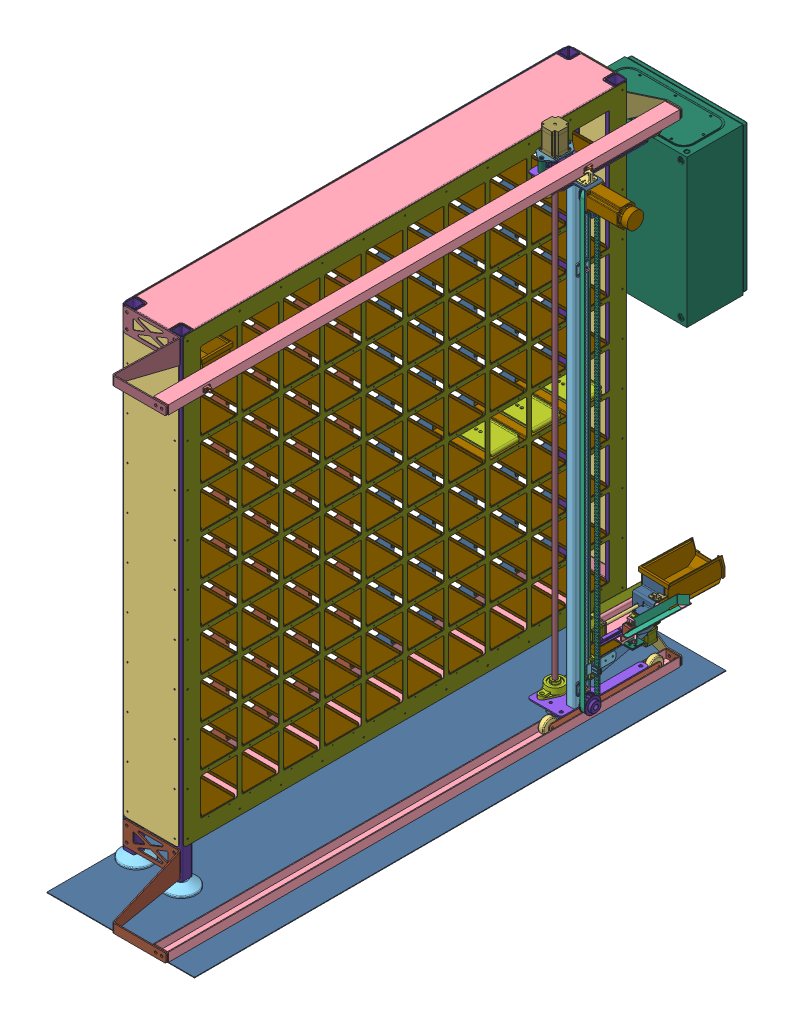
SolidWorks assembly T00000-000-R00, configuration Default. Lengths in mm.
Overall size (585.3 1705.5 1964.8).
258 component instances, 71 part files, 38 mates.
Components (placement in the parent):
- T00001-000-R00-1: T00001-000-R00 [Default] at (541.221 27.0951 939.139) size (309.78 1703.5 1858.33) (flexible)
  - T00118-000-R00-1: T00118-000-R00 [Default] at (157.9488 226.0018 -468.9511) size (25 25 300)
  - T00119-DXF-R00-1: T00119-DXF-R00 [Default] at (145.4488 226.0018 -318.9511) x (0 0 1) z (0 -1 0) size (380 3 25)
  - T00119-DXF-R00-2: T00119-DXF-R00 [Default] at (173.4488 226.0018 -318.9511) x (0 0 -1) z (0 1 0) size (380 3 25)
  - T00103-E00-R00-1: T00103-E00-R00 [Default] at (157.9488 226.0018 -138.9511) x (0 -0.996374 0.085085) z (0 0.085085 0.996374) size (50 22 50)
  - T00103-E00-R00-2: T00103-E00-R00 [Default] at (157.9488 226.0018 -498.9511) x (0 -1 0) z (0 0 1) size (50 22 50)
  - T00117-000-R00-1: T00117-000-R00 [Default] at (157.9488 198.0018 -560.9511) size (50 30 1732)
  - T00112-000-R00-1: T00112-000-R00 [50 x 30 x 2.6x1700] at (142.9488 1012.5018 -263.9511) x (1 0 0) z (0 -1 0) size (30 50 1540)
  - T00109-E00-R00-1: T00109-E00-R00 [HGR15R400CE20] at (157.9488 1772.5018 -263.9511) x (1 0 0) z (0 1 0) size (15 15 1530)
  - T00100-E00-R00-4: T00100-E00-R00 [Default] at (82.9488 242.5018 -238.9511) x (0 1 0) z (0 0 1) size (65.14 65.88 113)
  - T00120-DXF-R00-1: T00120-DXF-R00 [Default] at (100.4488 238.5018 -238.9511) x (0 0 -1) z (-1 0 0) size (300 4 115)
  - T00120-DXF-R00-2: T00120-DXF-R00 [Default] at (100.4488 1782.5018 -238.9511) x (0 0 -1) z (-1 0 0) size (300 4 115)
  - T00100-E00-R00-2: T00100-E00-R00 [Default] at (82.9488 1782.5018 -238.9511) x (0 -1 0) z (0 0 -1) size (65.14 65.88 113)
  - T00160-E00-R00-8: T00160-E00-R00 [Default] at (216.9488 1755.5018 -238.9511) x (0 0 1) z (-1 0 0) size (60 69 159.8)
  - T00121-0A4-R00-1: T00121-0A4-R00 [Default] at (216.9488 1751.5018 -238.9511) x (0 0 -1) z (0 -1 0) size (300 74 94)
  - T00103-E00-R00-3: T00103-E00-R00 [Default] at (157.9488 1803.0018 -138.9511) x (0 -1 0) z (0 0 1) size (50 22 50)
  - T00103-E00-R00-4: T00103-E00-R00 [Default] at (157.9488 1803.0018 -498.9511) x (0 0.952135 0.305677) z (0 0.305677 -0.952135) size (50 22 50)
  - T00119-DXF-R00-3: T00119-DXF-R00 [Default] at (173.4488 1803.0018 -318.9511) x (0 0 1) z (0 -1 0) size (380 3 25)
  - T00119-DXF-R00-4: T00119-DXF-R00 [Default] at (145.4488 1803.0018 -318.9511) x (0 0 -1) z (0 1 0) size (380 3 25)
  - T00118-000-R00-2: T00118-000-R00 [Default] at (157.9488 1803.0018 -168.9511) x (1 0 0) z (0 0 -1) size (25 25 300)
  - T00117-000-R00-2: T00117-000-R00 [Default] at (157.9488 1833.5018 -560.9511) x (-1 0 0) z (0 0 1) size (50 30 1732)
  - T00122-DXF-R00-1: T00122-DXF-R00 [Default] at (157.9488 213.0018 1175.0489) size (50 30 4)
  - T00122-DXF-R00-2: T00122-DXF-R00 [Default] at (157.9488 213.0018 -560.9511) size (50 30 4)
  - T00122-DXF-R00-3: T00122-DXF-R00 [Default] at (157.9488 1818.5018 -564.9511) x (-1 0 0) z (0 0 -1) size (50 30 4)
  - T00122-DXF-R00-4: T00122-DXF-R00 [Default] at (157.9488 1818.5018 1175.0489) size (50 30 4)
  - T00106-E00-R00-6: T00106-E00-R00 [Default] at (82.8989 1862.7018 -130.4663) x (-0.013505 0 0.999909) z (0 -1 0) size (56.4 57 96.6)
  - T00123-000-R00-1: T00123-000-R00 [Default] at (82.341 1823.9018 -238.9552) x (1 0 0) z (0 -1 0) size (15 15 1615)
  - T00124-DXF-R00-1: T00124-DXF-R00 [Default] at (82.341 1825.5018 -238.9552) x (-0.013505 0 0.999909) z (-0.999909 0 -0.013505) size (110 4 65)
  - T00104-E00-R00-1: T00104-E00-R00 [Default] at (82.9488 1786.5018 -193.9511) x (0 1 0) z (0 0 1) size (35 20 20)
  - T00104-E00-R00-2: T00104-E00-R00 [Default] at (82.9488 1786.5018 -283.9511) x (0 1 0) z (0 0 1) size (35 20 20)
  - T00101-E00-R00-1: T00101-E00-R00 [Default] at (112.9488 1791.0018 -193.9511) size (22 7 22)
  - T00101-E00-R00-2: T00101-E00-R00 [Default] at (112.9488 1791.0018 -283.9511) size (22 7 22)
  - T00101-E00-R00-3: T00101-E00-R00 [Default] at (112.9488 1798.0018 -283.9511) x (-0.837169 0 -0.546944) z (-0.546944 0 0.837169) size (22 7 22)
  - T00101-E00-R00-4: T00101-E00-R00 [Default] at (112.9488 1798.0018 -193.9511) x (-0.837169 0 -0.546944) z (-0.546944 0 0.837169) size (22 7 22)
  - T00101-E00-R00-5: T00101-E00-R00 [Default] at (112.9488 234.0018 -283.9511) size (22 7 22)
  - T00101-E00-R00-6: T00101-E00-R00 [Default] at (112.9488 227.0018 -283.9511) size (22 7 22)
  - T00101-E00-R00-7: T00101-E00-R00 [Default] at (112.9488 234.0018 -193.9511) x (-0.837169 0 -0.546944) z (-0.546944 0 0.837169) size (22 7 22)
  - T00101-E00-R00-8: T00101-E00-R00 [Default] at (112.9488 227.0018 -193.9511) x (-0.837169 0 -0.546944) z (-0.546944 0 0.837169) size (22 7 22)
  - T00102-E00-R00-1: T00102-E00-R00 [Default] at (82.341 237.5018 -238.9552) x (0 -1 0) z (-0.546944 0 0.837169) size (31 54 54)
  - T00102-E00-R00-2: T00102-E00-R00 [Default] at (82.341 1787.5018 -238.9552) x (0 1 0) z (0 0 1) size (31 54 54)
  - T00102-E00-R00-3: T00102-E00-R00 [Default] at (210.9488 1755.5018 -238.9511) x (-1 0 0) z (0 0.770219 0.637779) size (31 54 54)
  - T00125-0A4-R00-1: T00125-0A4-R00 [Default] at (137.9488 260.2518 -238.9511) x (0 0.966097 0.25818) z (0 0.25818 -0.966097) size (15 71.4 15)
  - T00102-E00-R00-5: T00102-E00-R00 [Default] at (189.9488 260.2518 -238.9511) x (1 0 0) z (0 0.748566 0.66306) size (31 54 54)
  - T00152-03D-R00-4: T00152-03D-R00 [Default] at (172.9488 297.5018 -239.1511) x (0 -1 0) z (0 0 1) size (40 4 40)
  - T00149-E00-R00-2: T00149-E00-R00 [Default] at (195.8488 1815.5018 -247.7511) x (0 0 1) z (0 1 0) size (22.7 14.9 13.4)
  - T00149-E00-R00-3: T00149-E00-R00 [Default] at (195.8488 1821.5018 1041.6323) x (0 0 -1) z (0 -1 0) size (22.7 14.9 13.4)
  - T00150-03D-R00-3: T00150-03D-R00 [Default] at (191.1488 1790.5018 -238.9511) x (0 0 -1) z (1 0 0) size (45 29.75 32)
  - T00153-E00-R00-1: T00153-E00-R00 [Default] at (180.9488 1523.996 -248.1511) x (0 -1 0) z (1 0 0) size (13 22.4 13.7)
  - T00151-03D-R00-1: T00151-03D-R00 [Default] at (172.9488 1527.496 -238.9511) x (0 -1 0) z (0 0 1) size (40 4 40)
  - T00153-E00-R00-2: T00153-E00-R00 [Default] at (180.9488 294.0018 -247.9534) x (0 -1 0) z (1 0 0) size (13 22.4 13.7)
  - T00166-E00-R00-1: T00166-E00-R00 [Default] at (193.6988 1755.5018 107.1126) x (0 0 -1) z (1 0 0) size (52.05 1547.3 15)
  - T00003-000-R00-2: T00003-000-R00 [Default] at (0 -530.7546 -533.6254) size (146.34 185.95 438.31)
    - T00108-E00-R00-3: T00108-E00-R00 [Default] at (157.9488 862.2474 269.7743) x (1 0 0) z (0 1 0) size (34 23.7 61.49)
    - T00110-E00-R00-1: T00110-E00-R00 [HGR15R400CE20] at (179.5179 918.7474 -31.6814) x (-0.999622 0 -0.027507) z (0.027507 0 -0.999622) size (15 15 270)
    - T00108-E00-R00-4: T00108-E00-R00 [Default] at (176.1354 919.5474 91.2378) x (-0.999622 0 -0.027507) z (0.027507 0 -0.999622) size (34 23.7 61.49)
    - T00148-E00-R00-1: T00148-E00-R00 [Default] at (211.9326 941.2474 40.4812) x (-0.999622 0 -0.027507) z (0.027507 0 -0.999622) size (104.77 76.2 187.32)
    - T00126-000-R00-1: T00126-000-R00 [Default] at (176.1354 950.5474 91.2378) x (-0.999622 0 -0.027507) z (0 1 0) size (75 74 94)
    - T00127-E00-R00-1: T00127-E00-R00 [DIN 625 - 6002 - 12,SI,NC,12_68] at (157.9488 901.2474 97.7743) x (0 1 0) z (0 0 1) size (9 32 32)
    - T00128-0A4-R00-1: T00128-0A4-R00 [Default] at (157.9488 887.7474 97.7743) x (1 0 0) z (0 -1 0) size (25 25 21)
    - T00129-E00-R00-1: T00129-E00-R00 [Circlip DIN 471 - 15 x 1.5] at (157.9488 905.9474 97.7743) x (0.837169 0 0.546944) z (0 -1 0) size (17.74 21.49 1.5)
    - T00130-0A4-R01-1: T00130-0A4-R01 [Default] at (157.9488 895.7474 97.7743) x (0.027507 0 -0.999622) z (0 -1 0) size (90 90 20)
    - T00132-E00-R00-4: T00132-E00-R00 [Metric - Spur gear 1M 60T 20PA 9FW ---S60N75H50L42N] at (157.9488 896.7474 97.7743) x (0 1 0) z (0 0 1) size (9 61.95 61.95)
    - T00107-E00-R00-1: T00107-E00-R00 [Varsayılan] at (157.9488 879.7474 61.7743) x (-1 0 0) z (0 1 0) size (42 58.5 65.65)
    - T00131-E00-R00-2: T00131-E00-R00 [Metric - Spur gear 1M 12T 20PA 8FW ---S12O10H14L5N] at (157.9488 896.7474 61.7743) x (0 1 0) z (0.924225 0 0.381849) size (14 13.61 13.61)
    - T00133-0A4-R00-3: T00133-0A4-R00 [Default] at (157.9488 862.2474 237.7743) x (1 0 0) z (0 1 0) size (49 210 57)
    - T00134-DXF-R00-1: T00134-DXF-R00 [Default] at (130.4488 892.7474 239.7743) x (0 0 -1) z (-1 0 0) size (155 44.25 3)
    - T00134-DXF-R00-2: T00134-DXF-R00 [Default] at (182.4488 892.7474 239.7743) x (0 0 -1) z (-1 0 0) size (155 44.25 3)
    - T00105-E00-R00-1: T00105-E00-R00 [Default] at (142.4488 890.7474 46.2743) x (1 0 0) z (0 -1 0) size (6 6 11)
    - T00105-E00-R00-2: T00105-E00-R00 [Default] at (173.4488 890.7474 46.2743) x (0.974973 0 -0.222324) z (0 -1 0) size (6 6 11)
    - T00105-E00-R00-3: T00105-E00-R00 [Default] at (142.4488 890.7474 77.2743) x (1 0 0) z (0 -1 0) size (6 6 11)
    - T00105-E00-R00-4: T00105-E00-R00 [Default] at (173.4488 890.7474 77.2743) x (1 0 0) z (0 -1 0) size (6 6 11)
    - T00107-E00-R00-2: T00107-E00-R00 [Varsayılan] at (132.7203 933.2474 196.6177) x (0.999622 0 0.027507) z (0.027507 0 -0.999622) size (42 58.5 65.65)
    - T00111-E00-R00-1: T00111-E00-R00 [Default] at (139.377 933.2474 -45.2907) x (0.577812 0.816015 0.0159) z (0.815706 -0.578031 0.022446) size (10 240 10)
    - T00135-DXF-R01-1: T00135-DXF-R01 [Default] at (158.3614 918.7474 82.78) x (-0.027507 0 0.999622) z (-0.999622 0 -0.027507) size (219 39 131)
    - T00136-DXF-R01-1: T00136-DXF-R01 [Default] at (187.4488 877.7474 233.7743) x (0 0 -1) z (1 0 0) size (94.88 30 25)
    - T00137-000-R00-1: T00137-000-R00 [gespiegeld] at (209.9194 941.2474 8.6701) x (0.027507 0 -0.999622) z (0.999622 0 0.027507) size (201.93 32 21.92)
    - T00138-000-R00-1: T00138-000-R00 [gespiegeld] at (111.9565 941.2474 5.9745) x (0.027507 0 -0.999622) z (0.999622 0 0.027507) size (201.93 32 21.92)
    - T00162-03D-R00-1: T00162-03D-R00 [Default] at (157.9488 905.7474 97.7743) x (0.027507 0 -0.999622) z (0 -1 0) size (22 26.53 4.1)
    - T00153-E00-R00-4: T00153-E00-R00 [Default] at (207.435 977.2474 171.6635) x (0.027507 0 -0.999622) z (0 1 0) size (13 22.4 13.7)
    - socket head cap screw_iso-1: socket head cap screw_iso [ISO 4762 M3 x 16 - 16N] at (223.2364 978.7474 179.1009) x (0 -1 0) z (0.997971 0 0.063667) size (19 5.5 5.5)
    - hex nut style 1 gradeab_iso-1: hex nut style 1 gradeab_iso [ISO - 4032 - M3 - W - N] at (223.2364 965.2474 179.1009) x (1 0 0) z (0 1 0) size (5.5 6.35 2.4)
    - socket head cap screw_iso-2: socket head cap screw_iso [ISO 4762 M3 x 16 - 16N] at (216.2391 978.7474 178.9084) x (0 -1 0) z (0 0 1) size (19 5.5 5.5)
    - socket head cap screw_iso-3: socket head cap screw_iso [ISO 4762 M3 x 8 - 8N] at (212.2406 949.2474 178.7984) x (-0.999622 0 -0.027507) z (0.027393 0.090831 -0.995489) size (11 5.5 5.5)
    - socket head cap screw_iso-4: socket head cap screw_iso [ISO 4762 M3 x 8 - 8N] at (212.2406 957.2474 178.7984) x (-0.999622 0 -0.027507) z (0.020371 -0.671964 -0.740304) size (11 5.5 5.5)
    - hex nut style 1 gradeab_iso-3: hex nut style 1 gradeab_iso [ISO - 4032 - M3 - W - N] at (216.2391 965.4397 178.9084) x (0.95019 0 0.311672) z (0 1 0) size (5.5 6.35 2.4)
    - hex nut style 1 gradeab_iso-4: hex nut style 1 gradeab_iso [ISO - 4032 - M3 - W - N] at (204.2436 957.2474 178.5783) x (0.020371 -0.671964 -0.740304) z (0.999622 0 0.027507) size (5.5 6.35 2.4)
    - hex nut style 1 gradeab_iso-5: hex nut style 1 gradeab_iso [ISO - 4032 - M3 - W - N] at (204.2436 949.2474 178.5783) x (0.020371 -0.671964 -0.740304) z (0.999622 0 0.027507) size (5.5 6.35 2.4)
    - socket head cap screw_iso-8: socket head cap screw_iso [ISO 4762 M4 x 10 - 10N] at (158.994 897.7474 59.7887) x (0 1 0) z (0.50631 0 0.862351) size (14 7 7)
    - T00153-E00-R00-7: T00153-E00-R00 [Default] at (120.7549 900.9974 134.9681) x (0.707107 0 0.707107) z (0 1 0) size (13 22.4 13.7)
    - T00153-E00-R00-8: T00153-E00-R00 [Default] at (195.1426 900.9974 134.9681) x (0.707107 0 -0.707107) z (0 1 0) size (13 22.4 13.7)
    - socket head cap screw_iso-11: socket head cap screw_iso [ISO 4762 M3 x 6 - 6N] at (168.9902 898.7474 60.0638) x (0 1 0) z (0 0 1) size (9 5.5 5.5)
    - socket head cap screw_iso-13: socket head cap screw_iso [ISO 4762 M3 x 6 - 6N] at (148.9978 898.7474 59.5136) x (0 1 0) z (-0.359477 0 -0.933154) size (9 5.5 5.5)
    - T00168-03D-R00-2: T00168-03D-R00 [Default] at (205.2432 959.2474 178.6058) x (0.027507 0 -0.999622) z (0.999622 0 0.027507) size (20 28 25.65)
    - T00163-03D-R00-1: T00163-03D-R00 [Default] at (179.6935 970.5474 52.8211) x (0.999622 0 0.027507) z (0 1 0) size (49 20 18.45)
    - T00161-0A4-R00-2: T00161-0A4-R00 [Default] at (157.9488 894.7474 147.7835) size (125 2 45)
    - T00164-03D-R00-1: T00164-03D-R00 [Default] at (157.9488 896.7474 147.7835) x (1 0 0) z (0 1 0) size (32 42.2 3)
    - T00165-03D-R00-1: T00165-03D-R00 [Default] at (250.9488 896.7474 147.7835) x (1 0 0) z (0 1 0) size (32 42.2 3)
- T00002-000-R00-1: T00002-000-R00 [Default] at (-702.7967 301.9782 1483.2641) x (0 0 -1) z (1 0 0) size (1575.8 1630 263)
  - T00114-DXF-R00-1: T00114-DXF-R00 [Default] at (354.4761 803.1187 1246.9664) size (1500 1500 2)
  - T00113-000-R00-9: T00113-000-R00 [40 x 40 x 3.2x1600] at (1070.8761 753.1187 1084.9664) x (0 0 -1) z (0 -1 0) size (40 40 1600)
  - T00113-000-R00-6: T00113-000-R00 [40 x 40 x 3.2x1600] at (-401.9239 753.1187 1204.9664) x (1 0 0) z (0 -1 0) size (40 40 1600)
  - T00113-000-R00-10: T00113-000-R00 [40 x 40 x 3.2x1600] at (-401.9239 753.1187 1084.9664) x (1 0 0) z (0 1 0) size (40 40 1600)
  - T00113-000-R00-8: T00113-000-R00 [40 x 40 x 3.2x1600] at (1070.8761 753.1187 1244.9664) x (1 0 0) z (0 1 0) size (40 40 1600)
  - T00116-0A4-R00-1: T00116-0A4-R00 [Default] at (-275.5239 1370.6187 1144.9664) x (0 0 -1) z (0 -1 0) size (200 114 23)
  - T00116-0A4-R00-2: T00116-0A4-R00 [Default] at (-275.5239 1230.6187 1144.9664) x (0 0 -1) z (0 -1 0) size (200 114 23)
  - T00116-0A4-R00-3: T00116-0A4-R00 [Default] at (-275.5239 1090.6187 1144.9664) x (0 0 -1) z (0 -1 0) size (200 114 23)
  - T00116-0A4-R00-4: T00116-0A4-R00 [Default] at (-275.5239 950.6187 1144.9664) x (0 0 -1) z (0 -1 0) size (200 114 23)
  - T00116-0A4-R00-5: T00116-0A4-R00 [Default] at (-275.5239 810.6187 1144.9664) x (0 0 -1) z (0 -1 0) size (200 114 23)
  - T00116-0A4-R00-6: T00116-0A4-R00 [Default] at (-275.5239 670.6187 1144.9664) x (0 0 -1) z (0 -1 0) size (200 114 23)
  - T00116-0A4-R00-7: T00116-0A4-R00 [Default] at (-275.5239 530.6187 1144.9664) x (0 0 -1) z (0 -1 0) size (200 114 23)
  - T00116-0A4-R00-8: T00116-0A4-R00 [Default] at (-275.5239 390.6187 1144.9664) x (0 0 -1) z (0 -1 0) size (200 114 23)
  - T00116-0A4-R00-9: T00116-0A4-R00 [Default] at (-275.5239 250.6187 1144.9664) x (0 0 -1) z (0 -1 0) size (200 114 23)
  - T00116-0A4-R00-10: T00116-0A4-R00 [Default] at (-275.5239 110.6187 1144.9664) x (0 0 -1) z (0 -1 0) size (200 114 23)
  - T00116-0A4-R00-11: T00116-0A4-R00 [Default] at (-135.5239 1370.6187 1144.9664) x (0 0 -1) z (0 -1 0) size (200 114 23)
  - T00116-0A4-R00-12: T00116-0A4-R00 [Default] at (-135.5239 1230.6187 1144.9664) x (0 0 -1) z (0 -1 0) size (200 114 23)
  - T00116-0A4-R00-13: T00116-0A4-R00 [Default] at (-135.5239 1090.6187 1144.9664) x (0 0 -1) z (0 -1 0) size (200 114 23)
  - T00116-0A4-R00-14: T00116-0A4-R00 [Default] at (-135.5239 950.6187 1144.9664) x (0 0 -1) z (0 -1 0) size (200 114 23)
  - T00116-0A4-R00-15: T00116-0A4-R00 [Default] at (-135.5239 810.6187 1144.9664) x (0 0 -1) z (0 -1 0) size (200 114 23)
  - T00116-0A4-R00-16: T00116-0A4-R00 [Default] at (-135.5239 670.6187 1144.9664) x (0 0 -1) z (0 -1 0) size (200 114 23)
  - T00116-0A4-R00-17: T00116-0A4-R00 [Default] at (-135.5239 530.6187 1144.9664) x (0 0 -1) z (0 -1 0) size (200 114 23)
  - T00116-0A4-R00-18: T00116-0A4-R00 [Default] at (-135.5239 390.6187 1144.9664) x (0 0 -1) z (0 -1 0) size (200 114 23)
  - T00116-0A4-R00-19: T00116-0A4-R00 [Default] at (-135.5239 250.6187 1144.9664) x (0 0 -1) z (0 -1 0) size (200 114 23)
  - T00116-0A4-R00-20: T00116-0A4-R00 [Default] at (-135.5239 110.6187 1144.9664) x (0 0 -1) z (0 -1 0) size (200 114 23)
  - T00116-0A4-R00-21: T00116-0A4-R00 [Default] at (4.4761 1370.6187 1144.9664) x (0 0 -1) z (0 -1 0) size (200 114 23)
  - T00116-0A4-R00-22: T00116-0A4-R00 [Default] at (4.4761 1230.6187 1144.9664) x (0 0 -1) z (0 -1 0) size (200 114 23)
  - T00116-0A4-R00-23: T00116-0A4-R00 [Default] at (4.4761 1090.6187 1144.9664) x (0 0 -1) z (0 -1 0) size (200 114 23)
  - T00116-0A4-R00-24: T00116-0A4-R00 [Default] at (4.4761 950.6187 1144.9664) x (0 0 -1) z (0 -1 0) size (200 114 23)
  - T00116-0A4-R00-25: T00116-0A4-R00 [Default] at (4.4761 810.6187 1144.9664) x (0 0 -1) z (0 -1 0) size (200 114 23)
  - T00116-0A4-R00-26: T00116-0A4-R00 [Default] at (4.4761 670.6187 1144.9664) x (0 0 -1) z (0 -1 0) size (200 114 23)
  - T00116-0A4-R00-27: T00116-0A4-R00 [Default] at (4.4761 530.6187 1144.9664) x (0 0 -1) z (0 -1 0) size (200 114 23)
  - T00116-0A4-R00-28: T00116-0A4-R00 [Default] at (4.4761 390.6187 1144.9664) x (0 0 -1) z (0 -1 0) size (200 114 23)
  - T00116-0A4-R00-29: T00116-0A4-R00 [Default] at (4.4761 250.6187 1144.9664) x (0 0 -1) z (0 -1 0) size (200 114 23)
  - T00116-0A4-R00-30: T00116-0A4-R00 [Default] at (4.4761 110.6187 1144.9664) x (0 0 -1) z (0 -1 0) size (200 114 23)
  - T00116-0A4-R00-31: T00116-0A4-R00 [Default] at (144.4761 1370.6187 1144.9664) x (0 0 -1) z (0 -1 0) size (200 114 23)
  - T00116-0A4-R00-32: T00116-0A4-R00 [Default] at (144.4761 1230.6187 1144.9664) x (0 0 -1) z (0 -1 0) size (200 114 23)
  - T00116-0A4-R00-33: T00116-0A4-R00 [Default] at (144.4761 1090.6187 1144.9664) x (0 0 -1) z (0 -1 0) size (200 114 23)
  - T00116-0A4-R00-34: T00116-0A4-R00 [Default] at (144.4761 950.6187 1144.9664) x (0 0 -1) z (0 -1 0) size (200 114 23)
  - T00116-0A4-R00-35: T00116-0A4-R00 [Default] at (144.4761 810.6187 1144.9664) x (0 0 -1) z (0 -1 0) size (200 114 23)
  - T00116-0A4-R00-36: T00116-0A4-R00 [Default] at (144.4761 670.6187 1144.9664) x (0 0 -1) z (0 -1 0) size (200 114 23)
  - T00116-0A4-R00-37: T00116-0A4-R00 [Default] at (144.4761 530.6187 1144.9664) x (0 0 -1) z (0 -1 0) size (200 114 23)
  - T00116-0A4-R00-38: T00116-0A4-R00 [Default] at (144.4761 390.6187 1144.9664) x (0 0 -1) z (0 -1 0) size (200 114 23)
  - T00116-0A4-R00-39: T00116-0A4-R00 [Default] at (144.4761 250.6187 1144.9664) x (0 0 -1) z (0 -1 0) size (200 114 23)
  - T00116-0A4-R00-40: T00116-0A4-R00 [Default] at (144.4761 110.6187 1144.9664) x (0 0 -1) z (0 -1 0) size (200 114 23)
  - T00116-0A4-R00-41: T00116-0A4-R00 [Default] at (284.4761 1370.6187 1144.9664) x (0 0 -1) z (0 -1 0) size (200 114 23)
  - T00116-0A4-R00-42: T00116-0A4-R00 [Default] at (284.4761 1230.6187 1144.9664) x (0 0 -1) z (0 -1 0) size (200 114 23)
  - T00116-0A4-R00-43: T00116-0A4-R00 [Default] at (284.4761 1090.6187 1144.9664) x (0 0 -1) z (0 -1 0) size (200 114 23)
  - T00116-0A4-R00-44: T00116-0A4-R00 [Default] at (284.4761 950.6187 1144.9664) x (0 0 -1) z (0 -1 0) size (200 114 23)
  - T00116-0A4-R00-45: T00116-0A4-R00 [Default] at (284.4761 810.6187 1144.9664) x (0 0 -1) z (0 -1 0) size (200 114 23)
  - T00116-0A4-R00-46: T00116-0A4-R00 [Default] at (284.4761 670.6187 1144.9664) x (0 0 -1) z (0 -1 0) size (200 114 23)
  - T00116-0A4-R00-47: T00116-0A4-R00 [Default] at (284.4761 530.6187 1144.9664) x (0 0 -1) z (0 -1 0) size (200 114 23)
  - T00116-0A4-R00-48: T00116-0A4-R00 [Default] at (284.4761 390.6187 1144.9664) x (0 0 -1) z (0 -1 0) size (200 114 23)
  - T00116-0A4-R00-49: T00116-0A4-R00 [Default] at (284.4761 250.6187 1144.9664) x (0 0 -1) z (0 -1 0) size (200 114 23)
  - T00116-0A4-R00-50: T00116-0A4-R00 [Default] at (284.4761 110.6187 1144.9664) x (0 0 -1) z (0 -1 0) size (200 114 23)
  - T00116-0A4-R00-51: T00116-0A4-R00 [Default] at (424.4761 1370.6187 1144.9664) x (0 0 -1) z (0 -1 0) size (200 114 23)
  - T00116-0A4-R00-52: T00116-0A4-R00 [Default] at (424.4761 1230.6187 1144.9664) x (0 0 -1) z (0 -1 0) size (200 114 23)
  - T00116-0A4-R00-53: T00116-0A4-R00 [Default] at (424.4761 1090.6187 1144.9664) x (0 0 -1) z (0 -1 0) size (200 114 23)
  - T00116-0A4-R00-54: T00116-0A4-R00 [Default] at (424.4761 950.6187 1144.9664) x (0 0 -1) z (0 -1 0) size (200 114 23)
  - T00116-0A4-R00-55: T00116-0A4-R00 [Default] at (424.4761 810.6187 1144.9664) x (0 0 -1) z (0 -1 0) size (200 114 23)
  - T00116-0A4-R00-56: T00116-0A4-R00 [Default] at (424.4761 670.6187 1144.9664) x (0 0 -1) z (0 -1 0) size (200 114 23)
  - T00116-0A4-R00-57: T00116-0A4-R00 [Default] at (424.4761 530.6187 1144.9664) x (0 0 -1) z (0 -1 0) size (200 114 23)
  - T00116-0A4-R00-58: T00116-0A4-R00 [Default] at (424.4761 390.6187 1144.9664) x (0 0 -1) z (0 -1 0) size (200 114 23)
  - T00116-0A4-R00-59: T00116-0A4-R00 [Default] at (424.4761 250.6187 1144.9664) x (0 0 -1) z (0 -1 0) size (200 114 23)
  - T00116-0A4-R00-60: T00116-0A4-R00 [Default] at (424.4761 110.6187 1144.9664) x (0 0 -1) z (0 -1 0) size (200 114 23)
  - T00116-0A4-R00-61: T00116-0A4-R00 [Default] at (564.4761 1370.6187 1144.9664) x (0 0 -1) z (0 -1 0) size (200 114 23)
  - T00116-0A4-R00-62: T00116-0A4-R00 [Default] at (564.4761 1230.6187 1144.9664) x (0 0 -1) z (0 -1 0) size (200 114 23)
  - T00116-0A4-R00-63: T00116-0A4-R00 [Default] at (564.4761 1090.6187 1144.9664) x (0 0 -1) z (0 -1 0) size (200 114 23)
  - T00116-0A4-R00-64: T00116-0A4-R00 [Default] at (564.4761 950.6187 1144.9664) x (0 0 -1) z (0 -1 0) size (200 114 23)
  - T00116-0A4-R00-65: T00116-0A4-R00 [Default] at (564.4761 810.6187 1144.9664) x (0 0 -1) z (0 -1 0) size (200 114 23)
  - T00116-0A4-R00-66: T00116-0A4-R00 [Default] at (564.4761 670.6187 1144.9664) x (0 0 -1) z (0 -1 0) size (200 114 23)
  - T00116-0A4-R00-67: T00116-0A4-R00 [Default] at (564.4761 530.6187 1144.9664) x (0 0 -1) z (0 -1 0) size (200 114 23)
  - T00116-0A4-R00-68: T00116-0A4-R00 [Default] at (564.4761 390.6187 1144.9664) x (0 0 -1) z (0 -1 0) size (200 114 23)
  - T00116-0A4-R00-69: T00116-0A4-R00 [Default] at (564.4761 250.6187 1144.9664) x (0 0 -1) z (0 -1 0) size (200 114 23)
  - T00116-0A4-R00-70: T00116-0A4-R00 [Default] at (564.4761 110.6187 1144.9664) x (0 0 -1) z (0 -1 0) size (200 114 23)
  - T00116-0A4-R00-71: T00116-0A4-R00 [Default] at (704.4761 1370.6187 1144.9664) x (0 0 -1) z (0 -1 0) size (200 114 23)
  - T00116-0A4-R00-72: T00116-0A4-R00 [Default] at (704.4761 1230.6187 1144.9664) x (0 0 -1) z (0 -1 0) size (200 114 23)
  - T00116-0A4-R00-73: T00116-0A4-R00 [Default] at (704.4761 1090.6187 1144.9664) x (0 0 -1) z (0 -1 0) size (200 114 23)
  - T00116-0A4-R00-74: T00116-0A4-R00 [Default] at (704.4761 950.6187 1144.9664) x (0 0 -1) z (0 -1 0) size (200 114 23)
  - T00116-0A4-R00-75: T00116-0A4-R00 [Default] at (704.4761 810.6187 1144.9664) x (0 0 -1) z (0 -1 0) size (200 114 23)
  - T00116-0A4-R00-77: T00116-0A4-R00 [Default] at (704.4761 530.6187 1144.9664) x (0 0 -1) z (0 -1 0) size (200 114 23)
  - T00116-0A4-R00-78: T00116-0A4-R00 [Default] at (704.4761 390.6187 1144.9664) x (0 0 -1) z (0 -1 0) size (200 114 23)
  - T00116-0A4-R00-79: T00116-0A4-R00 [Default] at (704.4761 250.6187 1144.9664) x (0 0 -1) z (0 -1 0) size (200 114 23)
  - T00116-0A4-R00-80: T00116-0A4-R00 [Default] at (704.4761 110.6187 1144.9664) x (0 0 -1) z (0 -1 0) size (200 114 23)
  - T00116-0A4-R00-81: T00116-0A4-R00 [Default] at (844.4761 1370.6187 1144.9664) x (0 0 -1) z (0 -1 0) size (200 114 23)
  - T00116-0A4-R00-82: T00116-0A4-R00 [Default] at (844.4761 1230.6187 1144.9664) x (0 0 -1) z (0 -1 0) size (200 114 23)
  - T00116-0A4-R00-83: T00116-0A4-R00 [Default] at (844.4761 1090.6187 1144.9664) x (0 0 -1) z (0 -1 0) size (200 114 23)
  - T00116-0A4-R00-84: T00116-0A4-R00 [Default] at (844.4761 950.6187 1144.9664) x (0 0 -1) z (0 -1 0) size (200 114 23)
  - T00116-0A4-R00-85: T00116-0A4-R00 [Default] at (844.4761 810.6187 1144.9664) x (0 0 -1) z (0 -1 0) size (200 114 23)
  - T00116-0A4-R00-87: T00116-0A4-R00 [Default] at (844.4761 530.6187 1144.9664) x (0 0 -1) z (0 -1 0) size (200 114 23)
  - T00116-0A4-R00-88: T00116-0A4-R00 [Default] at (844.4761 390.6187 1144.9664) x (0 0 -1) z (0 -1 0) size (200 114 23)
  - T00116-0A4-R00-89: T00116-0A4-R00 [Default] at (844.4761 250.6187 1144.9664) x (0 0 -1) z (0 -1 0) size (200 114 23)
  - T00116-0A4-R00-90: T00116-0A4-R00 [Default] at (844.4761 110.6187 1144.9664) x (0 0 -1) z (0 -1 0) size (200 114 23)
  - T00116-0A4-R00-91: T00116-0A4-R00 [Default] at (984.4761 1370.6187 1144.9664) x (0 0 -1) z (0 -1 0) size (200 114 23)
  - T00116-0A4-R00-92: T00116-0A4-R00 [Default] at (984.4761 1230.6187 1144.9664) x (0 0 -1) z (0 -1 0) size (200 114 23)
  - T00116-0A4-R00-93: T00116-0A4-R00 [Default] at (984.4761 1090.6187 1144.9664) x (0 0 -1) z (0 -1 0) size (200 114 23)
  - T00116-0A4-R00-94: T00116-0A4-R00 [Default] at (984.4761 950.6187 1144.9664) x (0 0 -1) z (0 -1 0) size (200 114 23)
  - T00116-0A4-R00-95: T00116-0A4-R00 [Default] at (984.4761 810.6187 1144.9664) x (0 0 -1) z (0 -1 0) size (200 114 23)
  - T00116-0A4-R00-97: T00116-0A4-R00 [Default] at (984.4761 530.6187 1144.9664) x (0 0 -1) z (0 -1 0) size (200 114 23)
  - T00116-0A4-R00-98: T00116-0A4-R00 [Default] at (984.4761 390.6187 1144.9664) x (0 0 -1) z (0 -1 0) size (200 114 23)
  - T00116-0A4-R00-99: T00116-0A4-R00 [Default] at (984.4761 250.6187 1144.9664) x (0 0 -1) z (0 -1 0) size (200 114 23)
  - T00116-0A4-R00-100: T00116-0A4-R00 [Default] at (984.4761 110.6187 1144.9664) x (0 0 -1) z (0 -1 0) size (200 114 23)
  - T00115-DXF-R01-1: T00115-DXF-R01 [Default] at (870.8674 -111.1162 2345.3532) x (-1 0 0) z (0 0 -1) size (1500 1500 2)
    - T00158-DXF-R00-1: T00158-DXF-R00 [Default] at (516.3913 914.2349 1302.3867) size (680 1500 2)
    - T00159-DXF-R00-1: T00159-DXF-R00 [Default] at (516.3913 914.2349 1302.3867) size (820 1500 2)
  - T00139-DXF-R00-1: T00139-DXF-R00 [Default] at (1112.8761 53.1187 1238.5664) x (0 0 -1) z (1 0 0) size (187.2 1500 2)
  - T00139-DXF-R00-2: T00139-DXF-R00 [Default] at (-403.9239 53.1187 1051.3664) x (0 0 1) z (-1 0 0) size (187.2 1500 2)
  - T00140-0A4-R00-1: T00140-0A4-R00 [Default] at (354.4761 1551.1187 1144.9664) x (1 0 0) z (0 -1 0) size (1512.8 200 40)
  - T00140-0A4-R00-2: T00140-0A4-R00 [Default] at (354.4761 55.1187 1144.9664) x (1 0 0) z (0 1 0) size (1512.8 200 40)
  - T00141-E00-R00-1: T00141-E00-R00 [SINGLE NUT] at (-374.1239 -76.8813 1065.1664) size (103 100 103)
  - T00141-E00-R00-2: T00141-E00-R00 [SINGLE NUT] at (-381.9239 -76.8813 1224.9664) size (103 100 103)
  - T00141-E00-R00-3: T00141-E00-R00 [SINGLE NUT] at (1090.8761 -76.8813 1064.9664) size (103 100 103)
  - T00141-E00-R00-4: T00141-E00-R00 [SINGLE NUT] at (1090.8761 -76.8813 1224.9664) size (103 100 103)
  - T00004-000-R00-1: T00004-000-R00 [Default] at (704.4761 655.6187 1144.9664) size (114 38.3 200)
    - T00157-E00-R00-1: T00157-E00-R00 [Default] at (0 9.15 27.5) x (0 0 -1) z (-1 0 0) size (80 12.7 12.7)
    - T00156-000-R00-1: T00156-000-R00 [Default] at (0 20.3 0) x (-1 0 0) z (0 1 0) size (106 182 17)
    - flat washer narrow_am-1: flat washer narrow_am [B18.22M - Plain washer, 5 mm, narrow] at (0 2.8 62.5) x (0 1 0) z (0 0 1) size (1.4 11 11)
    - flat washer narrow_am-2: flat washer narrow_am [B18.22M - Plain washer, 5 mm, narrow] at (0 2.8 47.5) x (0 1 0) z (0 0 1) size (1.4 11 11)
    - flat washer narrow_am-3: flat washer narrow_am [B18.22M - Plain washer, 5 mm, narrow] at (0 1.4 62.5) x (0 1 0) z (0 0 1) size (1.4 11 11)
    - flat washer narrow_am-4: flat washer narrow_am [B18.22M - Plain washer, 5 mm, narrow] at (0 1.4 47.5) x (0 1 0) z (-0.546944 0 0.837169) size (1.4 11 11)
    - flat washer narrow_am-7: flat washer narrow_am [B18.22M - Plain washer, 5 mm, narrow] at (0 15.5 -7.5) x (0 -1 0) z (-0.546944 0 0.837169) size (1.4 11 11)
    - flat washer narrow_am-8: flat washer narrow_am [B18.22M - Plain washer, 5 mm, narrow] at (0 16.9 -7.5) x (0 -1 0) z (0 0 1) size (1.4 11 11)
    - flat washer narrow_am-11: flat washer narrow_am [B18.22M - Plain washer, 5 mm, narrow] at (0 15.5 7.5) x (0 -1 0) z (-0.535309 0 -0.844656) size (1.4 11 11)
    - flat washer narrow_am-12: flat washer narrow_am [B18.22M - Plain washer, 5 mm, narrow] at (0 16.9 7.5) x (0 -1 0) z (0 0 1) size (1.4 11 11)
    - T00155-0A3-R00-3: T00155-0A3-R00 [Default] x (0 0 -1) z (0 1 0) size (200 114 23)
  - T00004-000-R00-2: T00004-000-R00 [Default] at (844.4761 655.6187 1144.9664) size (114 38.3 200)
    - T00157-E00-R00-1: T00157-E00-R00 [Default] at (0 9.15 27.5) x (0 0 -1) z (-1 0 0) size (80 12.7 12.7)
    - T00156-000-R00-1: T00156-000-R00 [Default] at (0 20.3 0) x (-1 0 0) z (0 1 0) size (106 182 17)
    - flat washer narrow_am-1: flat washer narrow_am [B18.22M - Plain washer, 5 mm, narrow] at (0 2.8 62.5) x (0 1 0) z (0 0 1) size (1.4 11 11)
    - flat washer narrow_am-2: flat washer narrow_am [B18.22M - Plain washer, 5 mm, narrow] at (0 2.8 47.5) x (0 1 0) z (0 0 1) size (1.4 11 11)
    - flat washer narrow_am-3: flat washer narrow_am [B18.22M - Plain washer, 5 mm, narrow] at (0 1.4 62.5) x (0 1 0) z (0 0 1) size (1.4 11 11)
    - flat washer narrow_am-4: flat washer narrow_am [B18.22M - Plain washer, 5 mm, narrow] at (0 1.4 47.5) x (0 1 0) z (-0.546944 0 0.837169) size (1.4 11 11)
    - flat washer narrow_am-7: flat washer narrow_am [B18.22M - Plain washer, 5 mm, narrow] at (0 15.5 -7.5) x (0 -1 0) z (-0.546944 0 0.837169) size (1.4 11 11)
    - flat washer narrow_am-8: flat washer narrow_am [B18.22M - Plain washer, 5 mm, narrow] at (0 16.9 -7.5) x (0 -1 0) z (0 0 1) size (1.4 11 11)
    - flat washer narrow_am-11: flat washer narrow_am [B18.22M - Plain washer, 5 mm, narrow] at (0 15.5 7.5) x (0 -1 0) z (-0.535309 0 -0.844656) size (1.4 11 11)
    - flat washer narrow_am-12: flat washer narrow_am [B18.22M - Plain washer, 5 mm, narrow] at (0 16.9 7.5) x (0 -1 0) z (0 0 1) size (1.4 11 11)
    - T00155-0A3-R00-3: T00155-0A3-R00 [Default] x (0 0 -1) z (0 1 0) size (200 114 23)
  - T00004-000-R00-3: T00004-000-R00 [Default] at (984.4761 655.6187 1144.9664) size (114 38.3 200)
    - T00157-E00-R00-1: T00157-E00-R00 [Default] at (0 9.15 27.5) x (0 0 -1) z (-1 0 0) size (80 12.7 12.7)
    - T00156-000-R00-1: T00156-000-R00 [Default] at (0 20.3 0) x (-1 0 0) z (0 1 0) size (106 182 17)
    - flat washer narrow_am-1: flat washer narrow_am [B18.22M - Plain washer, 5 mm, narrow] at (0 2.8 62.5) x (0 1 0) z (0 0 1) size (1.4 11 11)
    - flat washer narrow_am-2: flat washer narrow_am [B18.22M - Plain washer, 5 mm, narrow] at (0 2.8 47.5) x (0 1 0) z (0 0 1) size (1.4 11 11)
    - flat washer narrow_am-3: flat washer narrow_am [B18.22M - Plain washer, 5 mm, narrow] at (0 1.4 62.5) x (0 1 0) z (0 0 1) size (1.4 11 11)
    - flat washer narrow_am-4: flat washer narrow_am [B18.22M - Plain washer, 5 mm, narrow] at (0 1.4 47.5) x (0 1 0) z (-0.546944 0 0.837169) size (1.4 11 11)
    - flat washer narrow_am-7: flat washer narrow_am [B18.22M - Plain washer, 5 mm, narrow] at (0 15.5 -7.5) x (0 -1 0) z (-0.546944 0 0.837169) size (1.4 11 11)
    - flat washer narrow_am-8: flat washer narrow_am [B18.22M - Plain washer, 5 mm, narrow] at (0 16.9 -7.5) x (0 -1 0) z (0 0 1) size (1.4 11 11)
    - flat washer narrow_am-11: flat washer narrow_am [B18.22M - Plain washer, 5 mm, narrow] at (0 15.5 7.5) x (0 -1 0) z (-0.535309 0 -0.844656) size (1.4 11 11)
    - flat washer narrow_am-12: flat washer narrow_am [B18.22M - Plain washer, 5 mm, narrow] at (0 16.9 7.5) x (0 -1 0) z (0 0 1) size (1.4 11 11)
    - T00155-0A3-R00-3: T00155-0A3-R00 [Default] x (0 0 -1) z (0 1 0) size (200 114 23)
- T00147-E00-R00-1: T00147-E00-R00 [Default] at (562.1697 225.0969 1210.1879) x (0 0 1) z (0 1 0) size (1800 500 2)
- T00142-0A4-R00-2: T00142-0A4-R00 [Default] at (442.1697 310.0969 1885.1879) x (-1 0 0) z (0 0 -1) size (375.6 125.46 233)
- T00143-DXF-R00-1: T00143-DXF-R00 [Default] at (442.1697 310.0969 370.1879) x (-1 0 0) z (0 0 -1) size (375.6 125 4)
- T00143-DXF-R00-2: T00143-DXF-R00 [Default] at (442.1697 1775.5969 374.1879) x (-1 0 0) z (0 0 1) size (375.6 125 4)
- T00144-0A4-R00-1: T00144-0A4-R00 [Default] at (442.1697 1815.5969 1885.1879) x (-1 0 0) z (0 0 -1) size (375.6 85.45 233)
- T00145-E00-R00-1: T00145-E00-R00 [Default] at (654.1697 247.0969 745.1879) x (-0.837169 0 -0.546944) z (-0.546944 0 0.837169) size (22 7 22)
- T00145-E00-R00-2: T00145-E00-R00 [Default] at (654.1697 247.0969 655.1879) x (-0.837169 0 -0.546944) z (-0.546944 0 0.837169) size (22 7 22)
- T00146-E00-R00-1: T00146-E00-R00 [Default] at (540.1697 1725.0969 265.3879) x (1 0 0) z (0 0 -1) size (400 500 217)
- T00148-E00-R00-1: T00148-E00-R00 [Default] at (539.4947 1673.5969 1706.4004) x (0 0 1) z (-1 0 0) size (104.77 76.2 187.32)
- T00169-E00-R00-1: T00169-E00-R00 [Default] at (540.1697 1635.4469 163.7879) x (1 0 0) z (0 -1 0) size (166 14.1 124.15)
- T00170-03D-R00-1: T00170-03D-R00 [Default] at (540.1697 1635.4469 161.8879) x (-1 0 0) z (0 0 -1) size (184 131.9 18.8)
Mates (geometry in assembly coordinates):
- Distance1: distance = 130 mm: plane of T00002-000-R00-1/T00114-DXF-R00-1 through (544.1697 1105.0969 1128.7879) normal (1 0 0); plane of T00001-000-R00-1/T00117-000-R00-1 through (674.1697 225.0969 2110.1879) normal (-1 0 0)
- Distance2: distance = 225 mm: plane of T00002-000-R00-1/T00113-000-R00-6 through (508.5697 255.0969 1885.1879) normal (0 0 1); plane of T00001-000-R00-1/T00117-000-R00-1 through (699.1697 225.0969 2110.1879) normal (0 0 1)
- Distance3: distance = 30 mm: plane of T00001-000-R00-1/T00117-000-R00-1 through (674.1697 225.0969 2110.1879) normal (0 -1 0); plane of T00002-000-R00-1/T00113-000-R00-8 through (508.5697 255.0969 378.7879) normal (0 -1 0)
- Coincident4: coincident: plane of T00001-000-R00-1/T00117-000-R00-1 through (674.1697 225.0969 2110.1879) normal (0 -1 0); plane of T00147-E00-R00-1 through (562.1697 225.0969 1210.1879) normal (0 1 0)
- Distance4: distance = 30 mm: plane of T00147-E00-R00-1 through (312.1697 223.0969 310.1879) normal (-1 0 0); plane of T00002-000-R00-1/T00113-000-R00-10 through (342.1697 1855.0969 1851.5879) normal (-1 0 0)
- Coincident6: coincident: plane of T00001-000-R00-1/T00117-000-R00-1 through (699.1697 225.0969 2110.1879) normal (0 0 1); plane of T00147-E00-R00-1 through (312.1697 223.0969 2110.1879) normal (0 0 1)
- Coincident8: coincident: plane of T00002-000-R00-1/T00113-000-R00-10 through (375.7697 1855.0969 1885.1879) normal (0 0 1); plane of T00142-0A4-R00-2 through (442.1697 310.0969 1885.1879) normal (0 0 -1)
- Distance5: distance = 6.4 mm: plane of T00002-000-R00-1/T00113-000-R00-10 through (342.1697 1855.0969 1851.5879) normal (-1 0 0); plane of T00142-0A4-R00-2 through (348.5697 270.0969 1889.1879) normal (-1 0 0)
- Distance6: distance = 5 mm: plane of T00142-0A4-R00-2 through (535.7697 350.0969 1889.1879) normal (0 1 0); plane of T00002-000-R00-1/T00139-DXF-R00-2 through (358.5697 355.0969 1885.1879) normal (0 -1 0)
- Coincident9: coincident: plane of T00001-000-R00-1/T00122-DXF-R00-2 through (679.1697 230.0969 374.1879) normal (0 0 -1); plane of T00143-DXF-R00-1 through (442.1697 310.0969 374.1879) normal (0 0 1)
- Concentric1: concentric: cylinder of T00001-000-R00-1/T00122-DXF-R00-2 through (689.1697 240.0969 374.1879) axis (0 0 1) radius 4.25; cylinder of T00143-DXF-R00-1 through (689.1697 240.0969 374.1879) axis (0 0 -1) radius 4.25
- Concentric2: concentric: cylinder of T00001-000-R00-1/T00122-DXF-R00-2 through (709.1697 240.0969 374.1879) axis (0 0 1) radius 4.25; cylinder of T00143-DXF-R00-1 through (709.1697 240.0969 374.1879) axis (0 0 -1) radius 4.25
- Coincident10: coincident: plane of T00001-000-R00-1/T00122-DXF-R00-3 through (719.1697 1835.5969 374.1879) normal (0 0 -1); plane of T00143-DXF-R00-2 through (442.1697 1775.5969 374.1879) normal (0 0 1)
- Concentric3: concentric: cylinder of T00001-000-R00-1/T00122-DXF-R00-3 through (709.1697 1845.5969 378.1879) axis (0 0 -1) radius 4.25; cylinder of T00143-DXF-R00-2 through (709.1697 1845.5969 370.1879) axis (0 0 1) radius 4.25
- Concentric4: concentric: cylinder of T00001-000-R00-1/T00122-DXF-R00-3 through (689.1697 1845.5969 378.1879) axis (0 0 -1) radius 4.25; cylinder of T00143-DXF-R00-2 through (689.1697 1845.5969 370.1879) axis (0 0 1) radius 4.25
- Coincident11: coincident: plane of T00001-000-R00-1/T00122-DXF-R00-4 through (679.1697 1835.5969 2114.1879) normal (0 0 1); plane of T00144-0A4-R00-1 through (442.1697 1815.5969 2114.1879) normal (0 0 -1)
- Concentric5: concentric: cylinder of T00001-000-R00-1/T00122-DXF-R00-4 through (709.1697 1845.5969 2110.1879) axis (0 0 1) radius 4.25; cylinder of T00144-0A4-R00-1 through (709.1697 1845.5969 2108.1879) axis (0 0 1) radius 4.25
- Concentric6: concentric: cylinder of T00001-000-R00-1/T00122-DXF-R00-4 through (689.1697 1845.5969 2110.1879) axis (0 0 1) radius 4.25; cylinder of T00144-0A4-R00-1 through (689.1697 1845.5969 2108.1879) axis (0 0 1) radius 4.25
- Coincident12: coincident: plane of T00001-000-R00-1/T00101-E00-R00-8 through (649.9839 250.5969 742.4532) normal (0 -1 0); plane of T00145-E00-R00-1 through (649.9839 250.5969 742.4532) normal (0 1 0)
- Concentric7: concentric: cylinder of T00001-000-R00-1/T00101-E00-R00-8 through (654.1697 254.0969 745.1879) axis (0 -1 0) radius 11; cylinder of T00145-E00-R00-1 through (654.1697 247.0969 745.1879) axis (0 -1 0) radius 11
- Coincident13: coincident: plane of T00001-000-R00-1/T00101-E00-R00-6 through (659.1697 250.5969 655.1879) normal (0 -1 0); plane of T00145-E00-R00-2 through (649.9839 250.5969 652.4532) normal (0 1 0)
- Concentric8: concentric: cylinder of T00001-000-R00-1/T00101-E00-R00-6 through (654.1697 254.0969 655.1879) axis (0 1 0) radius 11; cylinder of T00145-E00-R00-2 through (654.1697 247.0969 655.1879) axis (0 -1 0) radius 11
- Coincident14: coincident: plane of T00002-000-R00-1/T00115-DXF-R01-1/T00158-DXF-R00-1 through (340.1697 1105.0969 1128.7879) normal (-1 0 0); plane of T00146-E00-R00-1 through (340.1697 1225.0969 370.3879) normal (-1 0 0)
- Coincident15: coincident: plane of T00002-000-R00-1/T00139-DXF-R00-1 through (525.7697 365.0969 370.3879) normal (0 0 -1); plane of T00146-E00-R00-1 through (740.1697 1225.0969 370.3879) normal (0 0 1)
- Distance7: distance = 130 mm: plane of T00002-000-R00-1/T00140-0A4-R00-1 through (442.1697 1855.0969 1128.7879) normal (0 1 0); plane of T00146-E00-R00-1 through (540.1697 1725.0969 265.3879) normal (0 1 0)
- Parallel1: parallel: plane of ? through (684.1697 1439.4029 826.9881) normal (0 1 0); plane of ? through (778.6697 1439.4029 890.1881) normal (0 -1 0)
- Coincident16: coincident: plane of ? through (684.1697 1439.4029 826.9881) normal (0 1 0); plane of ? through (778.6697 1439.4029 890.1881) normal (0 -1 0)
- Coincident17: coincident: plane of ? through (788.6697 1439.4029 892.4881) normal (0 0 1); plane of ? through (778.6697 1439.7029 892.4881) normal (0 0 1)
- Distance8: distance = 10 mm: plane of ? through (778.6697 1443.4029 878.4881) normal (1 0 0); plane of ? through (788.6697 1439.4029 872.4881) normal (1 0 0)
- Width1: width: plane of T00148-E00-R00-1 through (352.1697 1673.5969 1811.1754) normal (0 0 1); plane of T00148-E00-R00-1 through (352.1697 1673.5969 1706.4004) normal (0 0 -1); plane of T00002-000-R00-1/T00116-0A4-R00-1 through (442.1697 1672.5969 1814.7879) normal (0 0 -1); plane of T00002-000-R00-1/T00116-0A4-R00-1 through (442.1697 1672.5969 1702.7879) normal (0 0 1)
- Coincident19: coincident: plane of T00002-000-R00-1/T00116-0A4-R00-1 through (442.1697 1673.5969 1758.7879) normal (0 1 0); plane of T00148-E00-R00-1 through (352.1697 1673.5969 1706.4004) normal (0 -1 0)
- Distance9: distance = 10 mm: plane of T00148-E00-R00-1 through (352.1697 1673.5969 1706.4004) normal (-1 0 0); plane of T00002-000-R00-1/T00115-DXF-R01-1/T00159-DXF-R00-1 through (342.1697 1105.0969 1128.7879) normal (1 0 0)
- Width2: width: plane of T00146-E00-R00-1 through (340.1697 1225.0969 370.3879) normal (-1 0 0); plane of T00146-E00-R00-1 through (740.1697 1225.0969 180.3879) normal (1 0 0); plane of T00169-E00-R00-1 through (622.6697 1698.9234 137.7939) normal (1 0 0); plane of T00169-E00-R00-1 through (457.6697 1698.9234 137.7939) normal (-1 0 0)
- Coincident20: coincident: plane of T00146-E00-R00-1 through (732.1697 1233.0969 160.3879) normal (0 0 -1); plane of T00169-E00-R00-1 through (540.1697 1635.4469 160.3879) normal (0 0 -1)
- Width3: width: plane of T00169-E00-R00-1 through (622.6697 1586.8969 168.3879) normal (0 -1 0); plane of T00169-E00-R00-1 through (457.6697 1686.8969 168.3879) normal (0 1 0); plane of T00146-E00-R00-1 through (622.3697 1687.0969 170.3879) normal (0 -1 0); plane of T00146-E00-R00-1 through (622.3697 1586.6969 170.3879) normal (0 1 0)
- Concentric9: concentric: circle of T00169-E00-R00-1; cylinder of T00170-03D-R00-1 through (618.6697 1692.8969 166.6879) axis (0 0 -1) radius 1.8
- Concentric10: concentric: circle of T00169-E00-R00-1; cylinder of T00170-03D-R00-1 through (461.6697 1692.8969 166.6879) axis (0 0 -1) radius 1.8
- Coincident21: coincident: plane of T00169-E00-R00-1 through (540.1697 1635.4469 166.6879) normal (0 0 -1); plane of T00170-03D-R00-1 through (540.1697 1635.4469 166.6879) normal (0 0 1)
